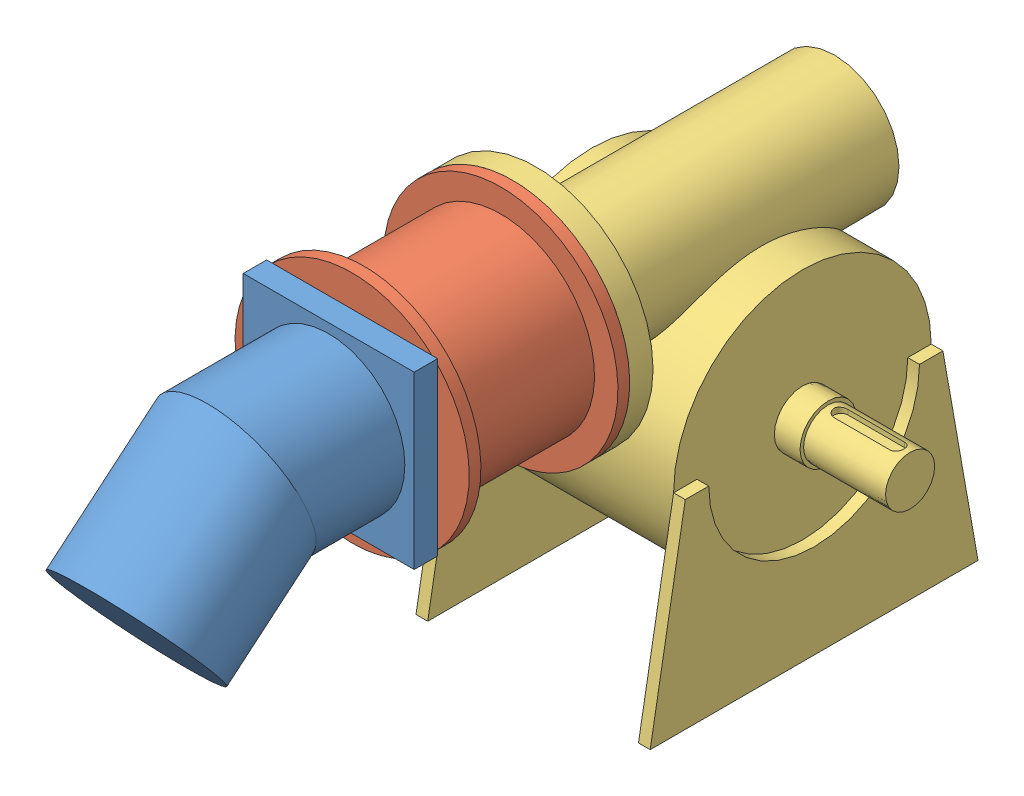
SolidWorks assembly hydraulic_motor_AA2FM_32, configuration Default. Lengths in mm.
Overall size (297.33 380 660.52).
3 component instances, 3 part files, 7 mates.
Components (placement in the parent):
- Motor-1: Motor [Default] at origin size (146 193.5 238.75)
- Flange_Adapter-1: Flange_Adapter [Default] x (0 0 -1) z (0 1 0) size (137 200 200)
- Wormgear-1: Wormgear [Default] at (0 0 -157) size (264.5 380 297.48)
Mates (geometry in assembly coordinates):
- Coincident1: coordinate: point of Motor-1
- Concentric1: concentric anti-aligned: cylinder of Motor-1 through (0 0 -12.7) axis (0 0 1) radius 63.5; cylinder of Flange_Adapter-1 through (0 0 -71.925) axis (0 0 -1) radius 60
- Coincident2: coincident anti-aligned: plane of Motor-1 through (0 0 0) normal (0 0 -1); plane of Flange_Adapter-1 through (-100 0 0) normal (0 0 1)
- Coincident3: coincident anti-aligned: plane of Flange_Adapter-1 through (-100 0 -137) normal (0 0 -1); plane of Wormgear-1 through (0 0 -137) normal (0 0 1)
- Concentric2: concentric aligned: cylinder of Flange_Adapter-1 through (0 0 -71.925) axis (0 0 -1) radius 80; cylinder of Wormgear-1 through (0 0 -137) axis (0 0 -1) radius 100
- Coincident4: coincident aligned: plane of Motor-1 through (0 0 0) normal (1 0 0); plane of Wormgear-1 through (0 0 -157) normal (1 0 0)
- Coincident5: coincident anti-aligned: plane of Motor-1 through (0 0 0) normal (1 0 0); plane of Flange_Adapter-1 through (0 0 0) normal (-1 0 0)
